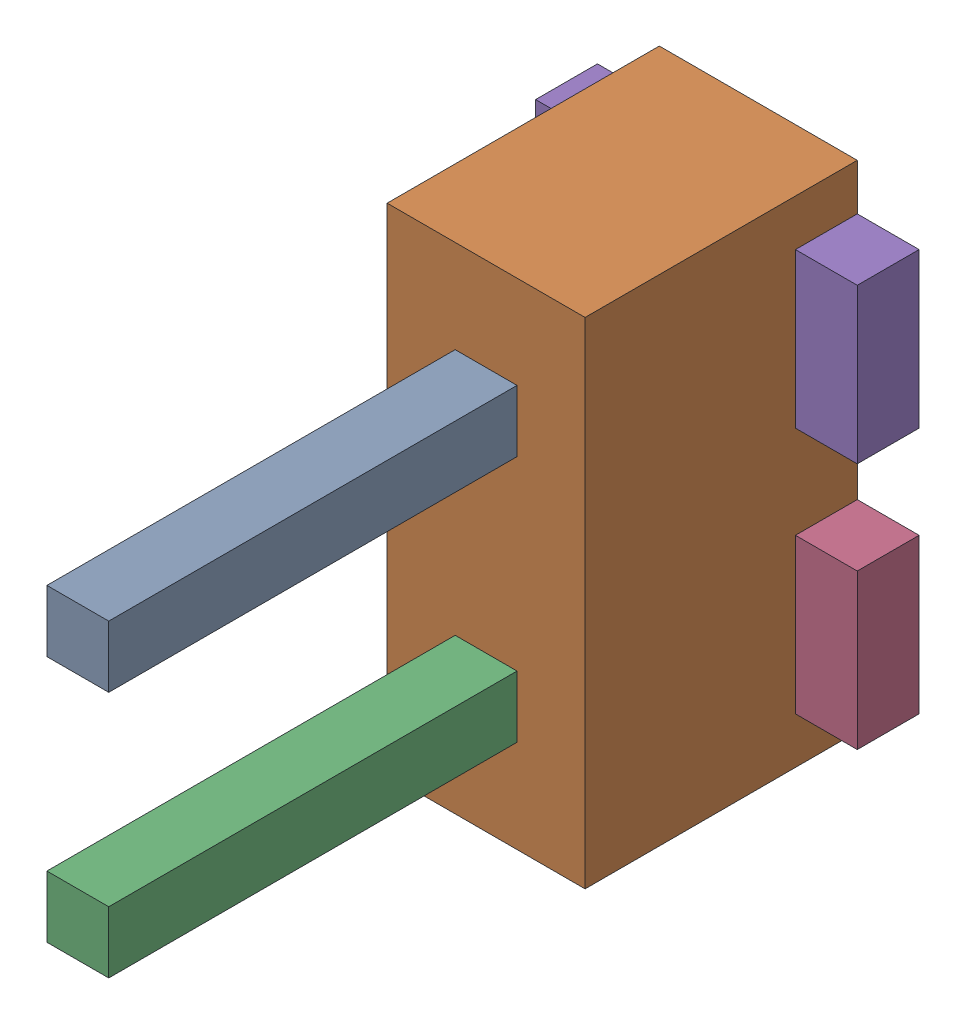
SolidWorks assembly J13, configuration ﾃﾞﾌｫﾙﾄ. Lengths in mm.
Overall size (2.6 4 5.5).
10 component instances, 3 part files, 0 mates.
Components (placement in the parent):
- 689260832-1: 689260832 [ﾃﾞﾌｫﾙﾄ] at (20.5 66.2501 2.2) size (0.5 0.5 3.3)
  - Extruded_26-1: Extruded_26 [ﾃﾞﾌｫﾙﾄ] at origin size (0.5 0.5 3.3)
- 689260968-1: 689260968 [ﾃﾞﾌｫﾙﾄ] at (20.5 65.25 0) size (1.6 4 2.2)
  - Extruded_27-1: Extruded_27 [ﾃﾞﾌｫﾙﾄ] at origin size (1.6 4 2.2)
- 689260832-2: 689260832 [ﾃﾞﾌｫﾙﾄ] at (20.5 64.2506 2.2) size (0.5 0.5 3.3)
  - Extruded_26-1: Extruded_26 [ﾃﾞﾌｫﾙﾄ] at origin size (0.5 0.5 3.3)
- 689261104-1: 689261104 [ﾃﾞﾌｫﾙﾄ] at (20.4999 64.2501 0) size (2.6 1.25 0.5)
  - Extruded_28-1: Extruded_28 [ﾃﾞﾌｫﾙﾄ] at origin size (2.6 1.25 0.5)
- 689261104-2: 689261104 [ﾃﾞﾌｫﾙﾄ] at (20.4999 66.2501 0) size (2.6 1.25 0.5)
  - Extruded_28-1: Extruded_28 [ﾃﾞﾌｫﾙﾄ] at origin size (2.6 1.25 0.5)
